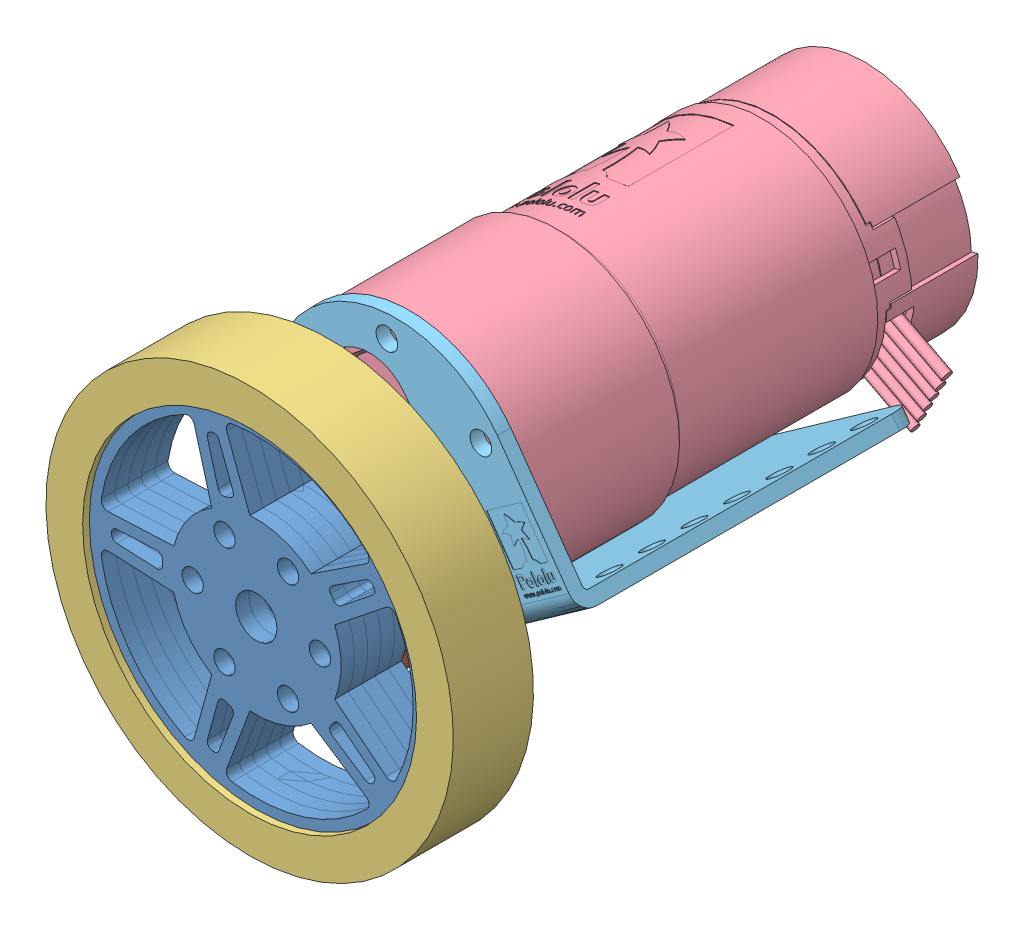
SolidWorks assembly Assem2, configuration Default. Lengths in mm.
Overall size (79.46 79.46 95.3).
13 component instances, 5 part files, 33 mates.
Components (placement in the parent):
- wheellayer-1: wheellayer [Default] at (0.056 0.28 58) x (0 1 0) z (1 0 0) size (59 2 59)
- wheellayer-3: wheellayer [Default] at (0.056 0.28 62) x (0 -1 0) z (1 0 0) size (59 2 59)
- wheellayer-4: wheellayer [Default] at (0.056 0.28 64) x (0 -1 0) z (1 0 0) size (59 2 59)
- wheellayer-5: wheellayer [Default] at (0.056 0.28 62) x (0 -1 0) z (1 0 0) size (59 2 59)
- wheellayer-6: wheellayer [Default] at (0.056 0.28 62) x (0 -1 0) z (1 0 0) size (59 2 59)
- wheellayer-7: wheellayer [Default] at (0.056 0.28 62) x (0 -1 0) z (1 0 0) size (59 2 59)
- wheellayer-9: wheellayer [Default] at (0.056 0.28 64) x (0 -1 0) z (1 0 0) size (59 2 59)
- wheellayer-11: wheellayer [Default] at (0.056 0.28 66) x (0 -1 0) z (1 0 0) size (59 2 59)
- wheellayer-14: wheellayer [Default] at (0.056 0.28 68) x (0 -1 0) z (1 0 0) size (59 2 59)
- hub-1: hub [Default] at (0.056 0.2801 55.5) x (-0.866025 -0.5 0) z (0 0 -1) size (25.4 25.4 9.2)
- tire-1: tire [Default] at (0.056 0.28 68) x (0.926665 0.375887 0) z (0 0 1) size (61 61 12)
- motor37d-1: motor37d [Default] at (-20.8504 -2.7081 21.875) x (0.887082 0.461612 0) z (0 0 1) size (36.88 41.23 90.1)
- L bracket-1: L bracket [Default] at (-1.7816 6.2498 36) x (0.816752 0.576989 0) z (0 0 1) size (37.59 39.6 51.2)
Mates (geometry in assembly coordinates):
- Coincident3: coincident anti-aligned: plane of wheellayer-1 through (0.056 0.28 60) normal (0 0 1); plane of wheellayer-3 through (0.056 0.28 60) normal (0 0 -1)
- Concentric2: concentric anti-aligned: cylinder of wheellayer-1 through (0.056 0.28 60) axis (0 0 -1) radius 3.1; cylinder of wheellayer-3 through (0.056 0.28 60) axis (0 0 1) radius 3.1
- Coincident8: coincident aligned: plane of wheellayer-1 through (-9.5423 -21.1705 60) normal (-0.964079 0.265616 0); plane of wheellayer-3 through (-9.5423 -21.1705 60) normal (-0.964079 0.265616 0)
- Coincident9: coincident anti-aligned: plane of wheellayer-3 through (0.056 0.28 62) normal (0 0 1); plane of wheellayer-4 through (0.056 0.28 62) normal (0 0 -1)
- Concentric4: concentric anti-aligned: cylinder of wheellayer-1 through (0.056 0.28 60) axis (0 0 -1) radius 3.1; cylinder of wheellayer-4 through (0.056 0.28 62) axis (0 0 1) radius 3.1
- Coincident10: coincident aligned: plane of wheellayer-1 through (-9.5423 -21.1705 60) normal (-0.964079 0.265616 0); plane of wheellayer-4 through (-9.5423 -21.1705 62) normal (-0.964079 0.265616 0)
- Concentric5: concentric anti-aligned: cylinder of wheellayer-1 through (0.056 0.28 60) axis (0 0 -1) radius 3.1; cylinder of wheellayer-5 through (0.056 0.28 60) axis (0 0 1) radius 3.1
- Coincident11: coincident aligned: plane of wheellayer-1 through (-9.5423 -21.1705 60) normal (-0.964079 0.265616 0); plane of wheellayer-5 through (-9.5423 -21.1705 60) normal (-0.964079 0.265616 0)
- Coincident12: coincident anti-aligned: plane of wheellayer-1 through (0.056 0.28 60) normal (0 0 1); plane of wheellayer-5 through (0.056 0.28 60) normal (0 0 -1)
- Coincident13: coincident anti-aligned: plane of wheellayer-1 through (0.056 0.28 60) normal (0 0 1); plane of wheellayer-6 through (0.056 0.28 60) normal (0 0 -1)
- Concentric6: concentric anti-aligned: cylinder of wheellayer-1 through (0.056 0.28 60) axis (0 0 -1) radius 3.1; cylinder of wheellayer-6 through (0.056 0.28 60) axis (0 0 1) radius 3.1
- Coincident14: coincident aligned: plane of wheellayer-1 through (-9.5423 -21.1705 60) normal (-0.964079 0.265616 0); plane of wheellayer-6 through (-9.5423 -21.1705 60) normal (-0.964079 0.265616 0)
- Coincident15: coincident anti-aligned: plane of wheellayer-1 through (0.056 0.28 60) normal (0 0 1); plane of wheellayer-7 through (0.056 0.28 60) normal (0 0 -1)
- Concentric7: concentric anti-aligned: cylinder of wheellayer-1 through (0.056 0.28 60) axis (0 0 -1) radius 3.1; cylinder of wheellayer-7 through (0.056 0.28 60) axis (0 0 1) radius 3.1
- Coincident17: coincident aligned: plane of wheellayer-1 through (-9.5423 -21.1705 60) normal (-0.964079 0.265616 0); plane of wheellayer-7 through (-9.5423 -21.1705 60) normal (-0.964079 0.265616 0)
- Coincident20: coincident anti-aligned: plane of wheellayer-3 through (0.056 0.28 62) normal (0 0 1); plane of wheellayer-9 through (0.056 0.28 62) normal (0 0 -1)
- Concentric9: concentric anti-aligned: cylinder of wheellayer-1 through (0.056 0.28 60) axis (0 0 -1) radius 3.1; cylinder of wheellayer-9 through (0.056 0.28 62) axis (0 0 1) radius 3.1
- Coincident21: coincident aligned: plane of wheellayer-1 through (-9.5423 -21.1705 60) normal (-0.964079 0.265616 0); plane of wheellayer-9 through (-9.5423 -21.1705 62) normal (-0.964079 0.265616 0)
- Coincident25: coincident anti-aligned: plane of wheellayer-4 through (0.056 0.28 64) normal (0 0 1); plane of wheellayer-11 through (0.056 0.28 64) normal (0 0 -1)
- Concentric12: concentric aligned: cylinder of wheellayer-4 through (0.056 0.28 62) axis (0 0 1) radius 3.1; cylinder of wheellayer-11 through (0.056 0.28 64) axis (0 0 1) radius 3.1
- Coincident26: coincident aligned: plane of wheellayer-6 through (-9.5423 -21.1705 60) normal (-0.964079 0.265616 0); plane of wheellayer-11 through (-9.5423 -21.1705 64) normal (-0.964079 0.265616 0)
- Coincident30: coincident anti-aligned: plane of wheellayer-11 through (0.056 0.28 66) normal (0 0 1); plane of wheellayer-14 through (0.056 0.28 66) normal (0 0 -1)
- Concentric14: concentric aligned: cylinder of wheellayer-4 through (0.056 0.28 62) axis (0 0 1) radius 3.1; cylinder of wheellayer-14 through (0.056 0.28 66) axis (0 0 1) radius 3.1
- Coincident31: coincident aligned: plane of wheellayer-6 through (-9.5423 -21.1705 60) normal (-0.964079 0.265616 0); plane of wheellayer-14 through (-9.5423 -21.1705 66) normal (-0.964079 0.265616 0)
- Coincident32: coincident anti-aligned: plane of wheellayer-1 through (0.056 0.28 58) normal (0 0 -1); plane of hub-1 through (0.056 0.28 58) normal (0 0 1)
- Concentric15: concentric anti-aligned: cylinder of wheellayer-6 through (0.056 0.28 60) axis (0 0 1) radius 3.1; cylinder of hub-1 through (0.056 0.28 58) axis (0 0 -1) radius 3
- Concentric16: concentric aligned: cylinder of wheellayer-1 through (-4.7065 -7.9689 60) axis (0 0 -1) radius 1.6; cylinder of hub-1 through (-4.7065 -7.9689 53) axis (0 0 -1) radius 1.25
- Concentric17: concentric aligned: cylinder of wheellayer-14 through (0.056 0.28 66) axis (0 0 1) radius 29.5; cylinder of tire-1 through (0.056 0.28 58) axis (0 0 1) radius 29.5
- Coincident33: coincident anti-aligned: plane of wheellayer-1 through (0.056 0.28 58) normal (0 0 -1); plane of tire-1 through (0.056 0.28 58) normal (0 0 1)
- Concentric18: concentric anti-aligned: cylinder of wheellayer-11 through (0.056 0.28 64) axis (0 0 1) radius 3.1; cylinder of motor37d-1 through (0.056 0.28 63.8) axis (0 0 -1) radius 3
- Distance1: distance = 1 mm anti-aligned: plane of hub-1 through (0.056 0.28 48.8) normal (0 0 -1); plane of motor37d-1 through (-3.1753 6.4895 47.8) normal (0 0 1)
- Concentric31: concentric: cylinder of motor37d-1 through (-3.1753 6.4895 19.8) axis (0 0 1) radius 18.4; cylinder of L bracket-1 through (-3.1753 6.4895 43.8) axis (0 0 1) radius 18.8
- Coincident35: coincident anti-aligned: plane of motor37d-1 through (-3.1753 6.4895 41.8) normal (0 0 1); plane of L bracket-1 through (23.0238 1.9797 41.8) normal (0 0 -1)
